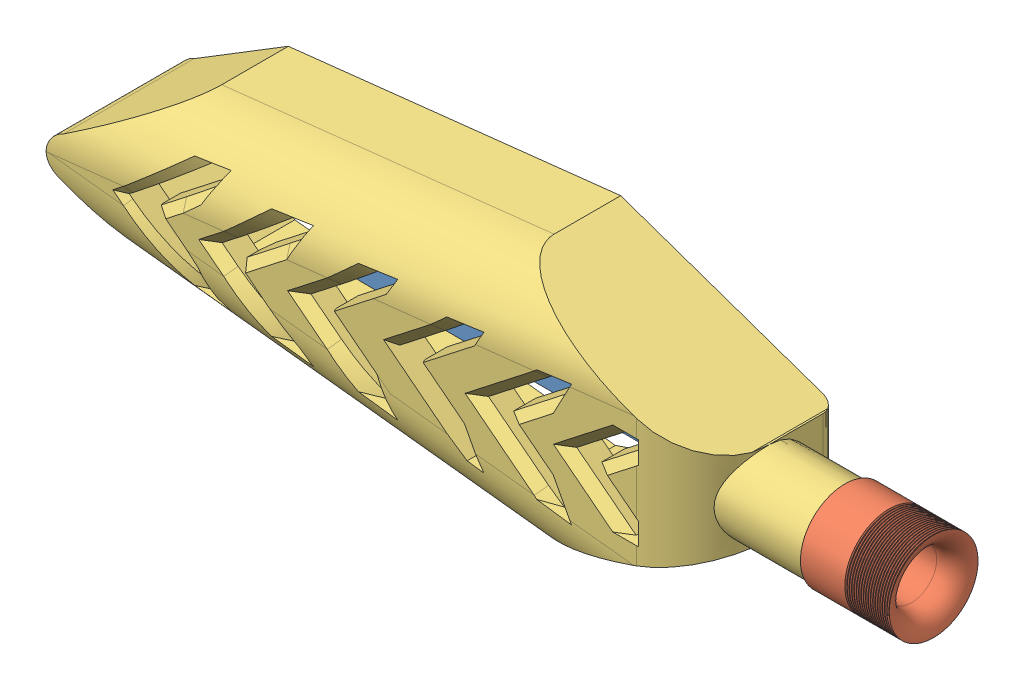
SolidWorks assembly Assem2, configuration Default. Lengths in mm.
Overall size (184.84 57.26 39.15).
4 component instances, 3 part files, 1 mates.
Components (placement in the parent):
- IND LED-1: IND LED [Default] at (-51.0073 72.1845 109.7844) size (100 15 4)
- ind right-1: ind right [Default] at (80.4056 53.5878 84.1308) x (1 0 0) z (0 -0.085189 0.996365) size (184.84 54.51 34.63)
  - ind thread-1: ind thread [Default] at (-15.6966 12.6871 30.1294) size (20 23.1 20)
  - indnew-1: indnew [Default] at (-107.7473 13.9711 45.1473) x (1 0 0) z (0 -0.085189 -0.996365) size (170.98 52.12 30.3)
Mates (geometry in assembly coordinates):
- Parallel3: parallel anti-aligned: plane of IND LED-1 through (-51.0073 72.1845 113.7844) normal (0 0 1); plane of ind right-1/indnew-1 through (-27.3416 63.6621 123.3042) normal (0 0 -1)
